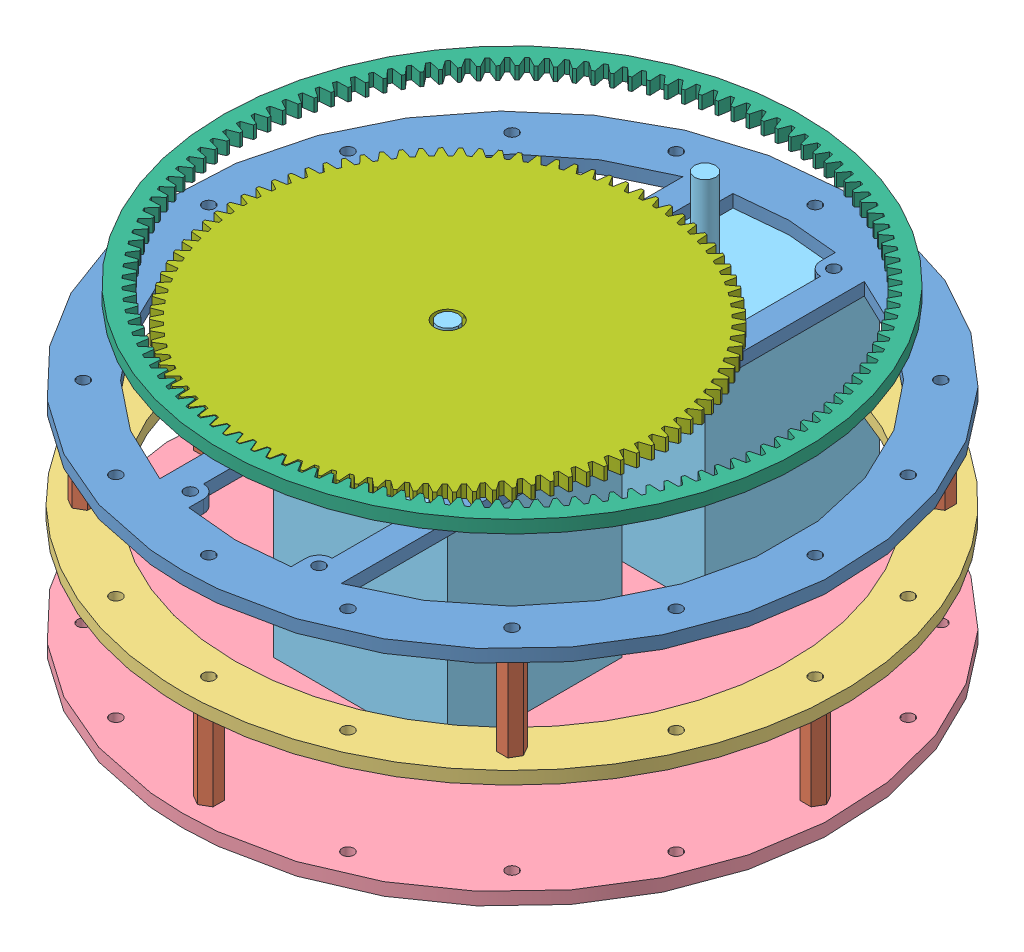
SolidWorks assembly Assem1, configuration Default. Lengths in mm.
Overall size (182.32 74.02 182.32).
17 component instances, 8 part files, 7 mates.
Components (placement in the parent):
- HousingSteppeMotor-1: HousingSteppeMotor [Default] at (24.9836 -31.8808 18.7779) size (158.75 74.02 158.75)
  - Base Unit-1: Base Unit [Default] at (-15.6008 25.016 -9.7985) size (158.75 3.05 158.75)
  - Part11^HousingSteppeMotor-1: Part11^HousingSteppeMotor [Default] at origin (virtual)
  - LHexStandoff-1: LHexStandoff [Default] at (-18.4264 2.7402 134.3541) x (0.866025 0 -0.5) z (0 1 0) size (5.46 4.72 22.28)
  - LHexStandoff-2: LHexStandoff [Default] at (128.5518 2.7402 -6.9729) x (-0.5 0 -0.866025) z (0 1 0) size (5.46 4.72 22.28)
  - LHexStandoff-3: LHexStandoff [Default] at (-12.7752 2.7402 -153.9512) x (-0.866025 0 0.5) z (0 1 0) size (5.46 4.72 22.28)
  - LHexStandoff-4: LHexStandoff [Default] at (-159.7534 2.7402 -12.6242) x (0.5 0 0.866025) z (0 1 0) size (5.46 4.72 22.28)
  - Generic Unit-1: Generic Unit [Default] at (-15.6008 -0.3078 -9.7985) size (158.75 3.05 158.75)
  - LHexStandoff-5: LHexStandoff [Default] at (33.21 -22.5836 9.6926) x (0.866025 0 -0.5) z (0 1 0) size (5.46 4.72 22.28)
  - LHexStandoff-6: LHexStandoff [Default] at (3.8904 -22.5836 -58.6094) x (-0.5 0 -0.866025) z (0 1 0) size (5.46 4.72 22.28)
  - LHexStandoff-7: LHexStandoff [Default] at (-64.4116 -22.5836 -29.2897) x (-0.866025 0 0.5) z (0 1 0) size (5.46 4.72 22.28)
  - LHexStandoff-8: LHexStandoff [Default] at (-35.092 -22.5836 39.0123) x (0.5 0 0.866025) z (0 1 0) size (5.46 4.72 22.28)
  - Bottom Panel-1: Bottom Panel [Default] at (-15.6008 -25.6316 -9.7985) size (158.75 3.05 158.75)
  - Stepper mock uo-1: Stepper mock uo [Default] at (-15.5754 1.521 -56.2559) x (1 0 0) z (0 1 0) size (42.01 42.01 70.36)
- Stepper mock uo-1: Stepper mock uo [Default] at (9.4082 -30.3598 24.4996) x (1 0 0) z (0 1 0) size (42.01 42.01 70.36)
- Internal Spur Gear_AI-1: Internal Spur Gear_AI [Inch - Internal spur gear 24DP 123T 20PA .12FW ---S123S5.5OD 1.0AF] at (9.3828 16.5032 8.9794) x (0 -1 0) z (-0.380154 0 0.924923) size (3.05 139.7 139.7)
- Large _AI-1: Large _AI [Inch - Spur gear 24DP 94T 20PA .12FW ---S94N3.0H2.0L0.25N] at (9.4082 16.5032 24.4996) x (0 -1 0) z (0.006604 0 0.999978) size (3.05 101.56 101.6)
Mates (geometry in assembly coordinates):
- Concentric1: concentric aligned: cylinder of HousingSteppeMotor-1/Base Unit-1 through (24.8768 -6.8648 39.9674) axis (0 1 0) radius 1.4224; circle of Stepper mock uo-1
- Parallel1: parallel aligned: plane of HousingSteppeMotor-1/Base Unit-1 through (31.2268 -6.8648 8.9794) normal (1 0 0); plane of Stepper mock uo-1 through (30.414 -6.8648 3.4946) normal (1 0 0)
- Coincident2: coincident anti-aligned: plane of HousingSteppeMotor-1/Base Unit-1 through (9.3828 -6.8648 8.9794) normal (0 -1 0); plane of Stepper mock uo-1 through (9.4082 -6.8648 24.4996) normal (0 1 0)
- Concentric3: concentric anti-aligned: cylinder of HousingSteppeMotor-1/Base Unit-1 through (9.3828 -3.8168 8.9794) axis (0 -1 0) radius 79.375; cylinder of Internal Spur Gear_AI-1 through (9.3828 26.5032 8.9794) axis (0 1 0) radius 69.85
- Coincident3: coincident aligned: plane of Stepper mock uo-1 through (9.4082 16.5032 24.4996) normal (0 1 0); plane of Internal Spur Gear_AI-1 through (33.7238 16.5032 -50.2427) normal (0 1 0)
- Concentric4: concentric anti-aligned: cylinder of Stepper mock uo-1 through (9.4082 16.5032 24.4996) axis (0 -1 0) radius 2.54; cylinder of Large _AI-1 through (9.4082 -34.2969 24.4996) axis (0 1 0) radius 3.175
- Coincident4: coincident aligned: plane of Stepper mock uo-1 through (9.4082 16.5032 24.4996) normal (0 1 0); plane of Large _AI-1 through (9.4082 16.5032 24.4996) normal (0 1 0)
